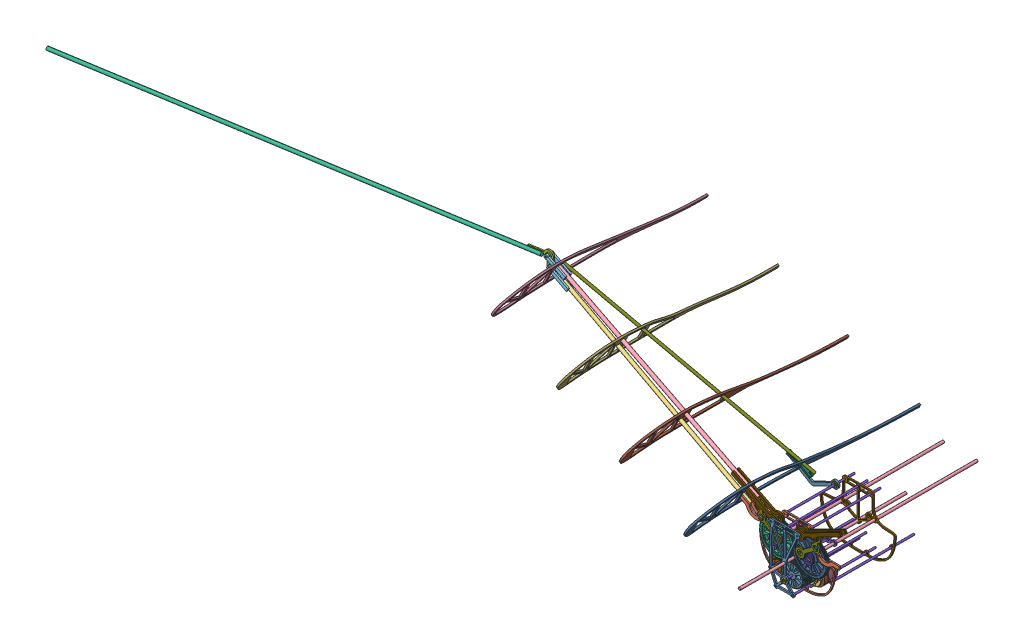
SolidWorks assembly Bird, configuration Default. Lengths in mm.
Overall size (1195.65 218.89 291.06).
74 component instances, 34 part files, 186 mates.
Components (placement in the parent):
- front-plate-sheet-1: front-plate-sheet [Default] at (23.6998 45.889 47.857) size (37.18 69.87 1.59)
- main-gear-sheet-1: main-gear-sheet [Default] at (27.6998 38.7802 32.2695) size (90.47 70.89 1.59)
- motor-mount-sheet-1: motor-mount-sheet [Default] at (23.6998 63.3802 26.2695) size (46 44.87 1.59)
- rod 3mm-1: rod 3mm [Default] at (27.6998 38.7802 103.1929) x (-0.690539 -0.723295 0) z (0 0 1) size (3 3 200)
- rod 3mm-2: rod 3mm [Default] at (7.6998 49.5302 37.857) x (-0.999697 -0.024626 0) z (0 0 1) size (3 3 200)
- rod 3mm-3: rod 3mm [Default] at (47.6998 49.5302 37.857) x (-0.465971 0.8848 0) z (0 0 1) size (3 3 200)
- 3x7mm-1: 3x7mm [Default] at (7.6998 49.5302 34.857) x (0.998777 0.049435 0) z (0 0 1) size (7 7 3)
- 3x7mm-2: 3x7mm [Default] at (47.6998 49.5302 34.857) x (0.999339 0.036342 0) z (0 0 1) size (7 7 3)
- 40mm 80T-1: 40mm 80T [Gear Blank] at (7.6998 49.5302 39.857) x (-0.995675 -0.092905 0) z (0 0 -1) size (41 41 5)
- 2x6x3mm-1: 2x6x3mm [Default] at (10.772 25.7276 32.857) x (-0.923728 -0.383049 0) z (0 0 -1) size (6 6 3)
- rod 2mm-1: rod 2mm [Default] at (17.8846 9.9139 -50.5555) x (-0.006595 0.999978 0) z (0 0 1) size (2 2 100)
- rod 2mm-2: rod 2mm [Default] at (37.5149 9.9139 -50.5555) x (0.478687 0.877986 0) z (0 0 1) size (2 2 100)
- rod 2mm-3: rod 2mm [Default] at (-12.7892 31.2227 -66.143) x (-0.311114 0.950373 0) z (0 0 1) size (2 2 100)
- rod 2mm-4: rod 2mm [Default] at (43.1998 74.5302 -50.5555) x (0.124758 0.992187 0) z (0 0 1) size (2 2 100)
- rod 2mm-5: rod 2mm [Default] at (12.1998 74.5302 -50.5555) x (0.128243 0.991743 0) z (0 0 1) size (2 2 100)
- rod 2mm-6: rod 2mm [Default] at (68.1888 31.2227 -66.143) x (0.415528 -0.90958 0) z (0 0 1) size (2 2 100)
- rod 2mm-7: rod 2mm [Default] at (10.772 25.7276 -50.5555) x (0.356707 -0.934216 0) z (0 0 1) size (2 2 100)
- rod 2mm-8: rod 2mm [Default] at (27.6998 74.5302 -50.5555) x (-0.312804 0.949818 0) z (0 0 1) size (2 2 100)
- 16-60 dual gear (6mm)-1: 16-60 dual gear (6mm) [Default] at (24.6479 25.9831 44.1759) x (0.280286 0.959916 0) z (0 0 1) size (31 31 11)
- 40mm 80T offset-1: 40mm 80T offset [Gear Blank] at (47.6998 49.5302 39.857) x (-0.998555 0.053744 0) z (0 0 -1) size (41 41 5)
- motor-1: motor [Varsayılan] at (41.9632 20.5223 39.6234) x (-0.707107 -0.707107 0) z (0 0 -1) size (28.46 28.46 36)
  - motor-taban-1: motor-taban [Varsayılan] at (-1.063 0.0213 13.3538) size (21 21 15.29)
  - motor-strator-1: motor-strator [Varsayılan] at (-1.063 0.0213 14.1462) x (-0.892183 0.451675 0) z (0 0 1) size (16.41 16.24 8.71)
  - motor-can-1: motor-can [Varsayılan] at (-1.063 0.0213 13.6462) x (-0.47572 0.879597 0) z (0 0 1) size (21 21 36)
- 10-50t dual gear-1: 10-50t dual gear [Default] at (28.1464 26.8366 25.7255) x (-0.859752 -0.510712 0) z (0 0 1) size (25.98 26 11)
- 2x6x3mm-2: 2x6x3mm [Default] at (27.6998 21.289 47.857) x (0.941098 0.338133 0) z (0 0 1) size (6 6 3)
- 2x6x3mm-3: 2x6x3mm [Default] at (27.6998 21.289 24.857) size (6 6 3)
- rod 2mm-9: rod 2mm [Default] at (27.6998 21.289 -49.143) x (0.680803 -0.732466 0) z (0 0 1) size (2 2 100)
- 10T 2mm bore pinion-1: 10T 2mm bore pinion [Gear Blank] at (42.6998 21.289 38.857) x (-0.66586 -0.746077 0) z (0 0 -1) size (6 6 10)
- link-1: link [Default] at (13.8674 53.9021 42.857) x (0.594759 0.803904 0) z (0 0 1) size (18.93 41.68 1.59)
- gear mount-1: gear mount [Default] at (-2.1782 3.169 39.857) x (0.995675 -0.092905 0) z (0 0 1) size (16.05 13.28 1.59)
- gear mount-2: gear mount [Default] at (-19.5287 111.9463 39.857) x (-0.417379 -0.908732 0) z (0 0 1) size (16.05 13.28 1.59)
- link-2: link [Default] at (41.5321 53.9021 44.447) x (-0.594759 0.803904 0) z (0 0 -1) size (18.93 41.68 1.59)
- wing root-1: wing root [Default] at (-6.1886 79.221 45.447) x (0.977458 -0.211132 0) z (0 0 1) size (302 82.72 2)
- wing root-2: wing root [Default] at (-6.1886 79.221 39.447) x (0.977458 -0.211132 0) z (0 0 1) size (302 82.72 2)
- wing root-3: wing root [Default] at (61.5881 79.221 47.037) x (-0.977458 -0.211132 0) z (0 0 -1) size (302 82.72 2)
- wing root-4: wing root [Default] at (61.5881 79.221 41.447) x (-0.977458 -0.211132 0) z (0 0 -1) size (302 82.72 2)
- 2x6x3mm-4: 2x6x3mm [Default] at (13.8674 53.9021 41.447) x (0.95095 0.309345 0) z (0 0 1) size (6 6 3)
- 2x6x3mm-5: 2x6x3mm [Default] at (41.5321 53.9021 41.447) x (0.95095 0.309345 0) z (0 0 1) size (6 6 3)
- 2x6x3mm-6: 2x6x3mm [Default] at (61.5881 79.221 41.447) x (0.95095 0.309345 0) z (0 0 1) size (6 6 3)
- 2x6x3mm-7: 2x6x3mm [Default] at (43.1998 74.5302 44.037) x (0.95095 0.309345 0) z (0 0 1) size (6 6 3)
- 2x6x3mm-8: 2x6x3mm [Default] at (-6.1886 79.221 41.447) x (0.95095 0.309345 0) z (0 0 1) size (6 6 3)
- 2x6x3mm-9: 2x6x3mm [Default] at (43.1998 74.5302 38.447) x (0.96189 0.273438 0) z (0 0 1) size (6 6 3)
- rod 2mm short-1: rod 2mm short [Default] at (61.5881 79.221 39.857) x (-0.312804 0.949818 0) z (0 0 1) size (2 2 8)
- rod 2mm short-2: rod 2mm short [Default] at (-6.1886 79.221 46.827) x (-0.312804 0.949818 0) z (0 0 1) size (2 2 8)
- 2x6x3mm-12: 2x6x3mm [Default] at (12.1998 74.5302 44.447) x (0.96189 0.273438 0) z (0 0 1) size (6 6 3)
- 2x6x3mm-13: 2x6x3mm [Default] at (12.1998 74.5302 38.447) x (0.96189 0.273438 0) z (0 0 1) size (6 6 3)
- actuator link bent-1: actuator link bent [Default] at (-4.7792 67.6976 45.447) x (0.989561 -0.144112 0) z (-0.144112 -0.989561 0) size (26.71 1.59 13.97)
- 2x6x3mm-14: 2x6x3mm [Default] at (-4.7792 67.6976 41.447) x (0.95095 0.309345 0) z (0 0 1) size (6 6 3)
- rod 2mm short-3: rod 2mm short [Default] at (-4.7792 67.6976 46.417) x (-0.312804 0.949818 0) z (0 0 1) size (2 2 8)
- actuator-1: actuator [Default] at (-6.0639 68.2512 43.4737) x (0.883027 -0.469323 0) z (0.107028 0.201373 0.97365) size (263.89 4 4)
- main spar-1: main spar [Default] at (2.7906 88.4475 48.7353) x (0.89269 -0.450672 0) z (0.244604 0.484512 -0.839891) size (270.64 4 4)
- 2x6x3mm-15: 2x6x3mm [Default] at (-257.2865 201.9035 42.447) x (-0.144801 -0.989461 0) z (0 0 1) size (6 6 3)
- 2x6x3mm-16: 2x6x3mm [Default] at (-260.6428 212.2739 42.447) x (-0.144801 -0.989461 0) z (0 0 1) size (6 6 3)
- rod 2mm short-4: rod 2mm short [Default] at (-257.2865 201.9035 46.827) x (0.989981 -0.141199 0) z (0 0 1) size (2 2 8)
- rod 2mm short-5: rod 2mm short [Default] at (-260.6428 212.2739 46.827) x (0.989981 -0.141199 0) z (0 0 1) size (2 2 8)
- actuator link-3: actuator link [Default] at (-260.6428 212.2739 39.447) x (-0.99237 0.123295 0) z (0.123295 0.99237 0) size (286.45 2 106.06)
- actuator link-4: actuator link [Default] at (-260.6428 212.2739 45.447) x (-0.99237 0.123295 0) z (0.123295 0.99237 0) size (286.45 2 106.06)
- actuator link-6: actuator link [Default] at (-257.2865 201.9035 39.447) x (-0.989561 0.144112 0) z (0.144112 0.989561 0) size (286.45 2 106.06)
- actuator link-7: actuator link [Default] at (-257.2865 201.9035 45.447) x (-0.989561 0.144112 0) z (0.144112 0.989561 0) size (286.45 2 106.06)
- actuator link bent-2: actuator link bent [Default] at (-4.7792 67.6976 39.857) x (0.989561 -0.144112 0) z (-0.144112 -0.989561 0) size (26.71 1.59 13.97)
- hand spar-1: hand spar [Default] at (-266.9264 211.3982 46.037) x (-0.011168 0.080129 -0.996722) z (-0.990427 -0.138036 0) size (4 4 600)
- joint-2: joint [Default] at (-257.2865 201.9035 42.447) x (0.951411 0.307925 0) z (0 0 1) size (30.96 22.8 1.59)
- rear support link-1: rear support link [Default] at (27.6998 38.7802 8.5681) size (46 17.13 1.59)
- rear large sheet-1: rear large sheet [Default] at (27.6998 38.7802 -40.5337) size (90.47 70.89 1.59)
- actuator link bent-10: actuator link bent [Default] at (60.8781 58.4075 41.447) x (-0.939246 0.343245 0) z (-0.343245 -0.939246 0) size (26.71 1.59 13.97)
- rib1-1: rib1 [Default] at (359.4585 846.6983 420.0886) x (0.89269 -0.450672 0) z (0.450672 0.89269 0) size (2 290.06 47.22)
- rib2-1: rib2 [Default] at (245.7355 811.2571 420.0886) x (0.89269 -0.450672 0) z (0.450672 0.89269 0) size (2 281.57 47.39)
- rib3-1: rib3 [Default] at (131.6194 775.0372 420.0886) x (0.89269 -0.450672 0) z (0.450672 0.89269 0) size (2 271.54 46.92)
- rib4-1: rib4 [Default] at (17.9807 739.7631 420.0886) x (0.89269 -0.450672 0) z (0.450672 0.89269 0) size (2 263.69 44.4)
- secondary root-1: secondary root [Default] at (12.1998 74.5302 -26.8269) x (-0.999998 -0.002177 0) z (0.002177 -0.999998 0) size (60.65 2 20.92)
- 2x6x3mm-20: 2x6x3mm [Default] at (12.1998 74.5302 -28.8269) x (0.96189 0.273438 0) z (0 0 1) size (6 6 3)
- secondary spar mount-1: secondary spar mount [Default] at (-19.1114 66.1726 -34.0472) x (-0.859481 0.511168 0) z (0 0 -1) size (29.79 2 10.44)
- secondary spar-1: secondary spar [Default] at (-16.9984 68.9882 -32.5953) x (-0.540081 -0.825896 -0.161889) z (-0.831916 0.494774 0.251225) size (3 3 279)
Mates (geometry in assembly coordinates):
- Concentric1: concentric aligned: cylinder of main-gear-sheet-1 through (17.8846 9.9139 33.857) axis (0 0 -1) radius 1; cylinder of motor-mount-sheet-1 through (17.8846 9.9139 27.857) axis (0 0 -1) radius 1
- Concentric2: concentric aligned: cylinder of main-gear-sheet-1 through (17.8846 9.9139 33.857) axis (0 0 -1) radius 1; cylinder of front-plate-sheet-1 through (17.8846 9.9139 49.4445) axis (0 0 -1) radius 1
- Concentric3: concentric aligned: cylinder of main-gear-sheet-1 through (27.6998 38.7802 33.857) axis (0 0 -1) radius 1.5; cylinder of motor-mount-sheet-1 through (27.6998 38.7802 27.857) axis (0 0 -1) radius 1.5
- Concentric4: concentric aligned: cylinder of main-gear-sheet-1 through (27.6998 38.7802 33.857) axis (0 0 -1) radius 1.5; cylinder of front-plate-sheet-1 through (27.6998 38.7802 49.4445) axis (0 0 -1) radius 1.5
- Concentric5: concentric anti-aligned: cylinder of motor-mount-sheet-1 through (27.6998 38.7802 27.857) axis (0 0 -1) radius 1.5; cylinder of rod 3mm-1 through (27.6998 38.7802 -96.8071) axis (0 0 1) radius 1.5
- Concentric7: concentric anti-aligned: cylinder of main-gear-sheet-1 through (47.6998 49.5302 33.857) axis (0 0 -1) radius 1.5; cylinder of rod 3mm-3 through (47.6998 49.5302 -162.143) axis (0 0 1) radius 1.5
- Concentric8: concentric anti-aligned: cylinder of motor-mount-sheet-1 through (7.6998 49.5302 27.857) axis (0 0 -1) radius 1.5; cylinder of rod 3mm-2 through (7.6998 49.5302 -162.143) axis (0 0 1) radius 1.5
- Concentric11: concentric anti-aligned: cylinder of rod 3mm-3 through (47.6998 49.5302 -162.143) axis (0 0 1) radius 1.5; cylinder of 3x7mm-2 through (47.6998 49.5302 37.857) axis (0 0 -1) radius 1.5
- Concentric12: concentric anti-aligned: cylinder of rod 3mm-2 through (7.6998 49.5302 -162.143) axis (0 0 1) radius 1.5; cylinder of 3x7mm-1 through (7.6998 49.5302 37.857) axis (0 0 -1) radius 1.5
- Concentric13: concentric anti-aligned: cylinder of 3x7mm-1 through (7.6998 49.5302 37.857) axis (0 0 -1) radius 3.5; cylinder of 40mm 80T-1 through (7.6998 49.5302 34.857) axis (0 0 1) radius 3.5
- Concentric14: concentric anti-aligned: cylinder of 3x7mm-2 through (47.6998 49.5302 44.7429) axis (0 0 -1) radius 3.5; cylinder of ? through (47.6998 49.5302 41.7429) axis (0 0 1) radius 3.5
- Distance1: distance = 1 mm anti-aligned: plane of 3x7mm-2 through (47.6998 49.5302 34.857) normal (0 0 -1); plane of main-gear-sheet-1 through (27.6998 38.7802 33.857) normal (0 0 1)
- Coincident7: coincident aligned: plane of 3x7mm-2 through (47.6998 49.5302 41.7429) normal (0 0 -1); plane of ? through (47.9996 69.7817 41.7429) normal (0 0 -1)
- Coincident8: coincident aligned: plane of 3x7mm-1 through (7.6998 49.5302 34.857) normal (0 0 -1); plane of 40mm 80T-1 through (6.1168 69.722 34.857) normal (0 0 -1)
- Coincident10: coincident aligned: plane of 3x7mm-1 through (7.6998 49.5302 34.857) normal (0 0 -1); plane of 3x7mm-2 through (47.6998 49.5302 34.857) normal (0 0 -1)
- Concentric16: concentric aligned: cylinder of front-plate-sheet-1 through (10.772 25.7276 49.4445) axis (0 0 -1) radius 0.75; cylinder of ? through (10.772 25.7276 80.4555) axis (0 0 -1) radius 0.75
- Concentric18: concentric anti-aligned: cylinder of ? through (10.772 25.7276 40.9691) axis (0 0 -1) radius 3; cylinder of 2x6x3mm-1 through (10.772 25.7276 36.9691) axis (0 0 1) radius 3
- Concentric19: concentric aligned: cylinder of front-plate-sheet-1 through (10.772 25.7276 49.4445) axis (0 0 -1) radius 1; cylinder of rod 2mm-7 through (10.772 25.7276 49.4445) axis (0 0 -1) radius 1
- Concentric20: concentric anti-aligned: cylinder of 2x6x3mm-1 through (10.772 25.7276 29.857) axis (0 0 1) radius 1; cylinder of rod 2mm-7 through (10.772 25.7276 49.4445) axis (0 0 -1) radius 1
- Distance3: distance = 1 mm aligned: plane of 2x6x3mm-1 through (10.772 25.7276 36.9691) normal (0 0 -1); plane of ? through (10.6831 10.4779 35.9691) normal (0 0 -1)
- Distance4: distance = 1 mm anti-aligned: plane of ? through (10.6831 10.4779 40.9691) normal (0 0 1); plane of 40mm 80T-1 through (20.7187 65.0454 41.9691) normal (0 0 -1)
- Concentric21: concentric anti-aligned: cylinder of 2x6x3mm-1 through (10.772 25.7276 29.857) axis (0 0 1) radius 3; cylinder of 16-60 dual gear (6mm)-1 through (10.772 25.7276 33.857) axis (0 0 -1) radius 3
- Distance5: distance = 1 mm anti-aligned: plane of 16-60 dual gear (6mm)-1 through (6.5942 26.6472 33.857) normal (0 0 -1); plane of 2x6x3mm-1 through (10.772 25.7276 32.857) normal (0 0 1)
- Coincident15: coincident aligned: plane of 40mm 80T-1 through (6.1168 69.722 39.857) normal (0 0 1); plane of 16-60 dual gear (6mm)-1 through (6.5942 26.6472 39.857) normal (0 0 1)
- GearMate3: gear = 16 : 80 mm: circle of 40mm 80T-1; circle of 16-60 dual gear (6mm)-1
- Concentric23: concentric aligned: cylinder of main-gear-sheet-1 through (17.8846 9.9139 33.857) axis (0 0 -1) radius 1; cylinder of rod 2mm-1 through (17.8846 9.9139 49.4445) axis (0 0 -1) radius 1
- Concentric24: concentric aligned: cylinder of main-gear-sheet-1 through (37.5149 9.9139 33.857) axis (0 0 -1) radius 1; cylinder of rod 2mm-2 through (37.5149 9.9139 49.4445) axis (0 0 -1) radius 1
- Concentric25: concentric aligned: cylinder of main-gear-sheet-1 through (-12.7892 31.2227 33.857) axis (0 0 -1) radius 1; cylinder of rod 2mm-3 through (-12.7892 31.2227 33.857) axis (0 0 -1) radius 1
- Concentric26: concentric aligned: cylinder of main-gear-sheet-1 through (68.1888 31.2227 33.857) axis (0 0 -1) radius 1; cylinder of rod 2mm-6 through (68.1888 31.2227 33.857) axis (0 0 -1) radius 1
- Concentric27: concentric aligned: cylinder of main-gear-sheet-1 through (12.1998 74.5302 33.857) axis (0 0 -1) radius 1; cylinder of rod 2mm-5 through (12.1998 74.5302 49.4445) axis (0 0 -1) radius 1
- Concentric28: concentric aligned: cylinder of main-gear-sheet-1 through (43.1998 74.5302 33.857) axis (0 0 -1) radius 1; cylinder of rod 2mm-4 through (43.1998 74.5302 49.4445) axis (0 0 -1) radius 1
- Concentric29: concentric aligned: cylinder of main-gear-sheet-1 through (27.6998 74.5302 33.857) axis (0 0 -1) radius 1; cylinder of rod 2mm-8 through (27.6998 74.5302 49.4445) axis (0 0 -1) radius 1
- Concentric36: concentric anti-aligned: cylinder of 3x7mm-2 through (47.6998 49.5302 37.857) axis (0 0 -1) radius 3.5; cylinder of 40mm 80T offset-1 through (47.6998 49.5302 34.857) axis (0 0 1) radius 3.5
- Coincident19: coincident aligned: plane of 40mm 80T-1 through (6.1168 69.722 39.857) normal (0 0 1); plane of 40mm 80T offset-1 through (49.0876 69.7363 39.857) normal (0 0 1)
- Concentric37: concentric anti-aligned: cylinder of motor-mount-sheet-1 through (42.6998 29.289 27.857) axis (0 0 -1) radius 1.05; cylinder of motor-1/motor-taban-1 through (42.6998 29.289 21.7695) axis (0 0 1) radius 1
- Concentric38: concentric anti-aligned: cylinder of motor-mount-sheet-1 through (42.6998 13.289 27.857) axis (0 0 -1) radius 1.05; cylinder of motor-1/motor-taban-1 through (42.6998 13.289 21.7695) axis (0 0 1) radius 1
- Coincident20: coincident anti-aligned: plane of motor-mount-sheet-1 through (7.6998 49.5302 26.2695) normal (0 0 -1); plane of motor-1/motor-taban-1 through (42.6998 21.289 26.2695) normal (0 0 1)
- Concentric39: concentric aligned: cylinder of motor-mount-sheet-1 through (42.6998 13.289 34.9446) axis (0 0 -1) radius 1.05; cylinder of ? through (42.6998 13.289 44.6736) axis (0 0 -1) radius 1.187
- Concentric40: concentric aligned: cylinder of front-plate-sheet-1 through (27.6998 21.289 49.4445) axis (0 0 -1) radius 3; cylinder of 2x6x3mm-2 through (27.6998 21.289 50.857) axis (0 0 -1) radius 3
- Concentric43: concentric aligned: cylinder of front-plate-sheet-1 through (27.6998 21.289 49.4445) axis (0 0 -1) radius 3; cylinder of motor-mount-sheet-1 through (27.6998 21.289 27.857) axis (0 0 -1) radius 3
- Concentric44: concentric aligned: cylinder of front-plate-sheet-1 through (27.6998 21.289 49.4445) axis (0 0 -1) radius 3; cylinder of 2x6x3mm-2 through (27.6998 21.289 50.857) axis (0 0 -1) radius 3
- Coincident21: coincident aligned: plane of front-plate-sheet-1 through (12.1998 74.5302 47.857) normal (0 0 -1); plane of 2x6x3mm-2 through (27.6998 21.289 47.857) normal (0 0 -1)
- Concentric45: concentric aligned: cylinder of motor-mount-sheet-1 through (27.6998 21.289 27.857) axis (0 0 -1) radius 3; cylinder of 2x6x3mm-3 through (27.6998 21.289 27.857) axis (0 0 -1) radius 3
- Coincident22: coincident aligned: plane of motor-mount-sheet-1 through (7.6998 49.5302 27.857) normal (0 0 1); plane of 2x6x3mm-3 through (27.6998 21.289 27.857) normal (0 0 1)
- Concentric46: concentric aligned: cylinder of 2x6x3mm-2 through (27.6998 21.289 50.857) axis (0 0 -1) radius 1; cylinder of rod 2mm-9 through (27.6998 21.289 50.857) axis (0 0 -1) radius 1
- Concentric47: concentric aligned: cylinder of 10-50t dual gear-1 through (27.6998 21.289 34.857) axis (0 0 -1) radius 1; cylinder of rod 2mm-9 through (27.6998 21.289 50.857) axis (0 0 -1) radius 1
- Coincident23: coincident aligned: plane of 16-60 dual gear (6mm)-1 through (6.5942 26.6472 39.857) normal (0 0 1); plane of 10-50t dual gear-1 through (23.9879 33.4851 39.857) normal (0 0 1)
- GearMate5: gear = 60 : 10 mm: cylinder of 10-50t dual gear-1 through (27.6998 21.289 39.857) axis (0 0 -1) radius 4; cylinder of 16-60 dual gear (6mm)-1 through (10.772 25.7276 28.857) axis (0 0 1) radius 6
- Distance6: distance = 8 mm anti-aligned: plane of 10-50t dual gear-1 through (23.9879 33.4851 39.857) normal (0 0 1); plane of front-plate-sheet-1 through (12.1998 74.5302 47.857) normal (0 0 -1)
- Distance7: distance = 1 mm anti-aligned: plane of motor-mount-sheet-1 through (7.6998 49.5302 27.857) normal (0 0 1); plane of 16-60 dual gear (6mm)-1 through (-3.9483 29.712 28.857) normal (0 0 -1)
- Concentric49: concentric anti-aligned: cylinder of motor-1/motor-can-1 through (42.6998 21.289 40.9772) axis (0 0 -1) radius 0.75; cylinder of 10T 2mm bore pinion-1 through (42.6998 21.289 29.857) axis (0 0 1) radius 1
- Coincident26: coincident aligned: plane of 10-50t dual gear-1 through (23.9879 33.4851 39.857) normal (0 0 1); plane of 10T 2mm bore pinion-1 through (40.8007 23.3514 39.857) normal (0 0 1)
- GearMate6: gear = 10 : 50 mm: cylinder of 10-50t dual gear-1 through (27.6998 21.289 39.857) axis (0 0 -1) radius 4; cylinder of 10T 2mm bore pinion-1 through (42.6998 21.289 33.857) axis (0 0 1) radius 3
- Coincident27: coincident aligned: plane of main-gear-sheet-1 through (27.6998 38.7802 33.857) normal (0 0 1); plane of rod 2mm-6 through (68.1888 31.2227 33.857) normal (0 0 1)
- Coincident28: coincident aligned: plane of main-gear-sheet-1 through (27.6998 38.7802 33.857) normal (0 0 1); plane of rod 2mm-3 through (-12.7892 31.2227 33.857) normal (0 0 1)
- Coincident29: coincident aligned: plane of front-plate-sheet-1 through (12.1998 74.5302 49.4445) normal (0 0 1); plane of rod 2mm-5 through (12.1998 74.5302 49.4445) normal (0 0 1)
- Coincident30: coincident aligned: plane of front-plate-sheet-1 through (12.1998 74.5302 49.4445) normal (0 0 1); circle of rod 2mm-4
- Coincident31: coincident aligned: plane of rod 3mm-3 through (47.6998 49.5302 37.857) normal (0 0 1); plane of 3x7mm-2 through (47.6998 49.5302 37.857) normal (0 0 1)
- Coincident32: coincident aligned: plane of rod 3mm-2 through (7.6998 49.5302 37.857) normal (0 0 1); plane of 3x7mm-1 through (7.6998 49.5302 37.857) normal (0 0 1)
- Coincident33: coincident aligned: plane of front-plate-sheet-1 through (12.1998 74.5302 49.4445) normal (0 0 1); plane of rod 2mm-2 through (37.5149 9.9139 49.4445) normal (0 0 1)
- Coincident34: coincident aligned: plane of 2x6x3mm-2 through (27.6998 21.289 50.857) normal (0 0 1); plane of rod 2mm-9 through (27.6998 21.289 50.857) normal (0 0 1)
- Coincident35: coincident aligned: plane of front-plate-sheet-1 through (12.1998 74.5302 49.4445) normal (0 0 1); plane of rod 2mm-7 through (10.772 25.7276 49.4445) normal (0 0 1)
- Coincident36: coincident aligned: plane of front-plate-sheet-1 through (12.1998 74.5302 49.4445) normal (0 0 1); plane of rod 2mm-1 through (17.8846 9.9139 49.4445) normal (0 0 1)
- Coincident37: coincident aligned: plane of front-plate-sheet-1 through (12.1998 74.5302 49.4445) normal (0 0 1); plane of rod 2mm-8 through (27.6998 74.5302 49.4445) normal (0 0 1)
- Concentric50: concentric anti-aligned: cylinder of 40mm 80T-1 through (7.6998 49.5302 34.857) axis (0 0 1) radius 3.5; cylinder of gear mount-2 through (7.6998 49.5302 41.447) axis (0 0 -1) radius 3.5
- Coincident38: coincident anti-aligned: plane of 40mm 80T-1 through (6.1168 69.722 39.857) normal (0 0 1); plane of gear mount-2 through (-19.5287 111.9463 39.857) normal (0 0 -1)
- Concentric51: concentric anti-aligned: cylinder of 40mm 80T-1 through (12.2434 47.4433 37.857) axis (0 0 1) radius 1.5; cylinder of gear mount-2 through (12.2434 47.4433 41.447) axis (0 0 -1) radius 0.575
- Concentric52: concentric anti-aligned: cylinder of 40mm 80T offset-1 through (47.6998 49.5302 34.857) axis (0 0 1) radius 3.5; cylinder of gear mount-1 through (47.6998 49.5302 41.447) axis (0 0 -1) radius 3.5
- Coincident39: coincident anti-aligned: plane of 40mm 80T offset-1 through (49.0876 69.7363 39.857) normal (0 0 1); plane of gear mount-1 through (-2.1782 3.169 39.857) normal (0 0 -1)
- Concentric53: concentric anti-aligned: cylinder of 40mm 80T offset-1 through (43.1561 47.4433 37.857) axis (0 0 1) radius 1.5; cylinder of gear mount-1 through (43.1561 47.4433 41.447) axis (0 0 -1) radius 0.575
- Concentric54: concentric aligned: cylinder of link-1 through (13.8674 53.9021 44.447) axis (0 0 -1) radius 3; cylinder of gear mount-2 through (13.8674 53.9021 41.447) axis (0 0 -1) radius 1
- Concentric55: concentric anti-aligned: cylinder of gear mount-1 through (41.5321 53.9021 41.447) axis (0 0 -1) radius 1; cylinder of link-2 through (41.5321 53.9021 42.857) axis (0 0 1) radius 3
- Concentric60: concentric anti-aligned: cylinder of rod 2mm-4 through (43.1998 74.5302 49.4445) axis (0 0 -1) radius 1; cylinder of wing root-3 through (43.1998 74.5302 45.037) axis (0 0 1) radius 3
- Concentric62: concentric anti-aligned: cylinder of rod 2mm-4 through (43.1998 74.5302 49.4445) axis (0 0 -1) radius 1; cylinder of wing root-4 through (43.1998 74.5302 39.447) axis (0 0 1) radius 3
- Concentric63: concentric aligned: cylinder of wing root-3 through (61.5881 79.221 45.037) axis (0 0 1) radius 1; cylinder of wing root-4 through (61.5881 79.221 39.447) axis (0 0 1) radius 1
- Concentric64: concentric aligned: cylinder of link-1 through (13.8674 53.9021 44.447) axis (0 0 -1) radius 3; cylinder of 2x6x3mm-4 through (13.8674 53.9021 44.447) axis (0 0 -1) radius 3
- Coincident46: coincident anti-aligned: plane of gear mount-2 through (-19.5287 111.9463 41.447) normal (0 0 1); plane of 2x6x3mm-4 through (13.8674 53.9021 41.447) normal (0 0 -1)
- Concentric65: concentric anti-aligned: cylinder of link-2 through (41.5321 53.9021 42.857) axis (0 0 1) radius 3; cylinder of 2x6x3mm-5 through (41.5321 53.9021 44.447) axis (0 0 -1) radius 3
- Coincident47: coincident anti-aligned: plane of gear mount-1 through (-2.1782 3.169 41.447) normal (0 0 1); plane of 2x6x3mm-5 through (41.5321 53.9021 41.447) normal (0 0 -1)
- Concentric68: concentric anti-aligned: cylinder of wing root-4 through (43.1998 74.5302 39.447) axis (0 0 1) radius 3; cylinder of 2x6x3mm-9 through (43.1998 74.5302 41.447) axis (0 0 -1) radius 3
- Concentric69: concentric anti-aligned: cylinder of wing root-3 through (43.1998 74.5302 45.037) axis (0 0 1) radius 3; cylinder of 2x6x3mm-7 through (43.1998 74.5302 47.037) axis (0 0 -1) radius 3
- Concentric70: concentric anti-aligned: cylinder of wing root-3 through (61.5881 79.221 45.037) axis (0 0 1) radius 1; cylinder of rod 2mm short-1 through (61.5881 79.221 43.3054) axis (0 0 -1) radius 1
- Concentric72: concentric aligned: cylinder of rod 2mm-5 through (12.1998 74.5302 49.4445) axis (0 0 -1) radius 1; cylinder of 2x6x3mm-13 through (12.1998 74.5302 41.447) axis (0 0 -1) radius 3
- Concentric73: concentric aligned: cylinder of 2x6x3mm-12 through (12.1998 74.5302 47.447) axis (0 0 -1) radius 3; cylinder of 2x6x3mm-13 through (12.1998 74.5302 41.447) axis (0 0 -1) radius 3
- Coincident66: coincident aligned: plane of link-1 through (13.8674 53.9021 44.447) normal (0 0 1); plane of 2x6x3mm-8 through (-6.1886 79.221 44.447) normal (0 0 1)
- Coincident71: coincident aligned: plane of link-2 through (41.5321 53.9021 44.447) normal (0 0 1); plane of 2x6x3mm-6 through (61.5881 79.221 44.447) normal (0 0 1)
- Coincident72: coincident aligned: plane of link-2 through (41.5321 53.9021 44.447) normal (0 0 1); plane of 2x6x3mm-5 through (41.5321 53.9021 44.447) normal (0 0 1)
- Coincident74: coincident aligned: plane of link-1 through (13.8674 53.9021 44.447) normal (0 0 1); plane of 2x6x3mm-4 through (13.8674 53.9021 44.447) normal (0 0 1)
- Concentric75: concentric anti-aligned: circle of actuator link bent-1; cylinder of ? through (-5.5274 56.9935 41.447) axis (0 0 -1) radius 1
- Coincident77: coincident aligned: plane of wing root-1 through (-14.2284 73.732 41.447) normal (0 0 1); plane of ? through (-5.5274 56.9935 41.447) normal (0 0 1)
- Concentric76: concentric aligned: cylinder of 2x6x3mm-8 through (-6.1886 79.221 44.447) axis (0 0 -1) radius 1; cylinder of rod 2mm short-2 through (-6.1886 79.221 50.2754) axis (0 0 -1) radius 1
- Concentric78: concentric aligned: cylinder of 2x6x3mm-6 through (61.5881 79.221 44.447) axis (0 0 -1) radius 1; cylinder of rod 2mm short-1 through (61.5881 79.221 43.3054) axis (0 0 -1) radius 1
- Concentric80: concentric aligned: cylinder of link-1 through (-4.7792 67.6976 44.447) axis (0 0 -1) radius 3; cylinder of 2x6x3mm-14 through (-4.7792 67.6976 44.447) axis (0 0 -1) radius 3
- Coincident78: coincident aligned: plane of link-1 through (13.8674 53.9021 44.447) normal (0 0 1); plane of 2x6x3mm-14 through (-4.7792 67.6976 44.447) normal (0 0 1)
- Concentric83: concentric aligned: cylinder of actuator link bent-1 through (-4.7792 67.6976 47.037) axis (0 0 -1) radius 1; cylinder of rod 2mm short-3 through (-4.7792 67.6976 49.8654) axis (0 0 -1) radius 1
- Coincident80: coincident aligned: plane of actuator link bent-1 through (-4.7792 67.6976 47.037) normal (0 0 1); plane of rod 2mm short-3 through (-10.0286 69.3391 47.037) normal (0 0 1)
- Coincident81: coincident aligned: plane of actuator link bent-1; plane of ? through (-5.2612 58.9757 41.447) normal (0.133091 0.991104 0)
- Concentric84: concentric aligned: cylinder of wing root-1 through (-6.1886 79.221 47.447) axis (0 0 -1) radius 1; cylinder of rod 2mm short-2 through (-6.1886 79.221 50.2754) axis (0 0 -1) radius 1
- Tangent1: tangent anti-aligned: plane of actuator link bent-1 through (-4.7792 67.6976 45.447) normal (0 0 -1); cylinder of actuator-1 through (-251.5468 198.8529 43.447) axis (0.883027 -0.469323 0) radius 2
- Tangent2: tangent aligned: plane of actuator link bent-1 through (-3.8406 69.4636 47.037) normal (0.469323 0.883027 0); cylinder of actuator-1 through (-251.5468 198.8529 43.447) axis (0.883027 -0.469323 0) radius 2
- Coincident84: coincident aligned: plane of ? through (-185.4714 321.1453 42.447) normal (0 0 -1); plane of 2x6x3mm-16 through (-180.1902 331.9207 42.447) normal (0 0 -1)
- Coincident85: coincident aligned: plane of ? through (-185.4714 321.1453 42.447) normal (0 0 -1); plane of 2x6x3mm-15 through (-185.4714 321.1453 42.447) normal (0 0 -1)
- Concentric86: concentric aligned: cylinder of 2x6x3mm-15 through (-257.2865 201.9035 45.447) axis (0 0 -1) radius 1; cylinder of rod 2mm short-4 through (-257.2865 201.9035 50.2754) axis (0 0 -1) radius 1
- Concentric87: concentric aligned: cylinder of 2x6x3mm-16 through (-260.6428 212.2739 45.447) axis (0 0 -1) radius 1; cylinder of rod 2mm short-5 through (-260.6428 212.2739 50.2754) axis (0 0 -1) radius 1
- Concentric88: concentric aligned: cylinder of rod 2mm short-5 through (-260.6428 212.2739 50.2754) axis (0 0 -1) radius 1; cylinder of actuator link-3 through (-260.6428 212.2739 41.447) axis (0 0 -1) radius 1
- Concentric89: concentric aligned: cylinder of rod 2mm short-5 through (-260.6428 212.2739 50.2754) axis (0 0 -1) radius 1; cylinder of actuator link-4 through (-260.6428 212.2739 47.447) axis (0 0 -1) radius 1
- Concentric90: concentric aligned: cylinder of rod 2mm short-4 through (-257.2865 201.9035 50.2754) axis (0 0 -1) radius 1; cylinder of actuator link-7 through (-257.2865 201.9035 47.447) axis (0 0 -1) radius 1
- Concentric91: concentric aligned: cylinder of rod 2mm short-4 through (-257.2865 201.9035 50.2754) axis (0 0 -1) radius 1; cylinder of actuator link-6 through (-257.2865 201.9035 41.447) axis (0 0 -1) radius 1
- Coincident86: coincident aligned: plane of rod 2mm short-5 through (-256.8423 216.2495 47.447) normal (0 0 1); plane of actuator link-4 through (-260.6428 212.2739 47.447) normal (0 0 1)
- Coincident87: coincident aligned: plane of rod 2mm short-4 through (-253.4859 205.8792 47.447) normal (0 0 1); plane of actuator link-7 through (-257.2865 201.9035 47.447) normal (0 0 1)
- Coincident89: coincident anti-aligned: plane of 2x6x3mm-16 through (-260.6428 212.2739 45.447) normal (0 0 1); plane of actuator link-4 through (-260.6428 212.2739 45.447) normal (0 0 -1)
- Coincident90: coincident aligned: plane of actuator link-3 through (-261.5442 210.4885 41.447) normal (-0.450672 -0.89269 0); plane of actuator link-4 through (-261.5442 210.4885 47.447) normal (-0.450672 -0.89269 0)
- Coincident92: coincident anti-aligned: plane of 2x6x3mm-15 through (-257.2865 201.9035 45.447) normal (0 0 1); plane of actuator link-7 through (-257.2865 201.9035 45.447) normal (0 0 -1)
- Coincident93: coincident aligned: plane of actuator link-6 through (-258.2251 200.1375 41.447) normal (-0.469323 -0.883027 0); plane of actuator link-7 through (-258.2251 200.1375 47.447) normal (-0.469323 -0.883027 0)
- Coincident95: coincident aligned: plane of rod 2mm short-5 through (-260.6428 212.2739 39.447) normal (0 0 -1); plane of actuator link-3 through (-260.6428 212.2739 39.447) normal (0 0 -1)
- Coincident96: coincident aligned: plane of rod 2mm short-4 through (-257.2865 201.9035 39.447) normal (0 0 -1); plane of actuator link-6 through (-257.2865 201.9035 39.447) normal (0 0 -1)
- Tangent8: tangent anti-aligned: cylinder of main spar-1 through (-250.8233 207.3165 43.447) axis (0.89269 -0.450672 0) radius 2; plane of actuator link-3 through (-260.6428 212.2739 41.447) normal (0 0 1)
- Tangent10: tangent aligned: cylinder of main spar-1 through (-250.8233 207.3165 43.447) axis (0.89269 -0.450672 0) radius 2; plane of actuator link-3 through (-259.7415 214.0593 41.447) normal (0.450672 0.89269 0)
- Coincident99: coincident aligned: plane of actuator link bent-1 through (-3.8406 69.4636 47.037) normal (0.469323 0.883027 0); plane of actuator link-7 through (-256.3478 203.6696 47.447) normal (0.469323 0.883027 0)
- Concentric92: concentric aligned: cylinder of rod 2mm short-3 through (-4.7792 67.6976 49.8654) axis (0 0 -1) radius 1; cylinder of actuator link bent-2 through (-4.7792 67.6976 41.447) axis (0 0 -1) radius 1
- Coincident101: coincident aligned: plane of actuator link bent-1 through (-3.8406 69.4636 47.037) normal (0.469323 0.883027 0); plane of actuator link bent-2 through (-3.8406 69.4636 41.447) normal (0.469323 0.883027 0)
- Tangent15: tangent anti-aligned: plane of ? through (-185.4714 321.1453 44.037) normal (0 0 1); cylinder of hand spar-1 through (-724.1365 598.52 46.037) axis (0.897947 -0.440103 0) radius 2
- Concentric93: concentric aligned: cylinder of ? through (-180.1902 331.9207 44.037) axis (0 0 -1) radius 3; cylinder of 2x6x3mm-16 through (-180.1902 331.9207 45.447) axis (0 0 -1) radius 3
- Concentric95: concentric aligned: cylinder of ? through (-185.4714 321.1453 44.037) axis (0 0 -1) radius 3; cylinder of 2x6x3mm-15 through (-185.4714 321.1453 45.447) axis (0 0 -1) radius 3
- Tangent17: tangent anti-aligned: plane of ? through (-185.4714 321.1453 44.037) normal (0 0 1); cylinder of hand spar-1 through (-724.1365 598.52 46.037) axis (0.897947 -0.440103 0) radius 2
- Tangent18: tangent aligned: plane of ? through (-179.31 333.7166 44.037) normal (0.440103 0.897947 0); cylinder of hand spar-1 through (-724.1365 598.52 46.037) axis (0.897947 -0.440103 0) radius 2
- Coincident104: coincident: line of ? through (-184.4878 336.2543 44.037) axis (0 0 -1); plane of hand spar-1
- Distance14: distance = 5 mm anti-aligned: plane of main spar-1; cylinder of ? through (-180.1902 331.9207 44.037) axis (0 0 -1) radius 5.5
- Distance15: distance = 5 mm anti-aligned: cylinder of ? through (-185.4714 321.1453 44.037) axis (0 0 -1) radius 5.5; plane of actuator-1
- Concentric101: concentric aligned: cylinder of actuator link bent-1 through (-4.7792 67.6976 47.037) axis (0 0 -1) radius 2.5; cylinder of 2x6x3mm-14 through (-4.7792 67.6976 44.447) axis (0 0 -1) radius 1
- Coincident106: coincident: plane of actuator-1 through (-18.5267 75.0042 43.447) normal (0.883027 -0.469323 0); line of actuator link bent-2 through (-17.588 76.7703 41.447) axis (0 0 -1)
- Concentric102: concentric anti-aligned: cylinder of link-2 through (61.5881 79.221 42.857) axis (0 0 1) radius 3; cylinder of 2x6x3mm-6 through (61.5881 79.221 44.447) axis (0 0 -1) radius 3
- Coincident112: coincident aligned: plane of wing root-1 through (-11.4379 80.8625 47.447) normal (0 0 1); plane of 2x6x3mm-12 through (12.1998 74.5302 47.447) normal (0 0 1)
- Concentric106: concentric aligned: cylinder of wing root-1 through (12.1998 74.5302 47.447) axis (0 0 -1) radius 3; cylinder of 2x6x3mm-12 through (12.1998 74.5302 47.447) axis (0 0 -1) radius 3
- Tangent26: tangent aligned: plane of wing root-1 through (6.9649 79.4134 47.447) normal (0.450672 0.89269 0); cylinder of main spar-1 through (-250.8233 207.3165 43.447) axis (0.89269 -0.450672 0) radius 2
- Distance16: distance = 23 mm anti-aligned: cylinder of rod 2mm-5 through (12.1998 74.5302 49.4445) axis (0 0 -1) radius 1; plane of main spar-1 through (-9.2248 85.3463 43.447) normal (0.89269 -0.450672 0)
- Coincident118: coincident anti-aligned: plane of 2x6x3mm-14 through (-4.7792 67.6976 41.447) normal (0 0 -1); plane of actuator link bent-2 through (-4.7792 67.6976 41.447) normal (0 0 1)
- Coincident119: coincident aligned: plane of actuator link-4 through (-260.6428 212.2739 47.447) normal (0 0 1); plane of actuator link-7 through (-257.2865 201.9035 47.447) normal (0 0 1)
- Concentric114: concentric aligned: cylinder of 2x6x3mm-16 through (-260.6428 212.2739 45.447) axis (0 0 -1) radius 3; cylinder of joint-2 through (-260.6428 212.2739 44.037) axis (0 0 -1) radius 3
- Concentric115: concentric aligned: cylinder of 2x6x3mm-15 through (-257.2865 201.9035 45.447) axis (0 0 -1) radius 3; cylinder of joint-2 through (-257.2865 201.9035 44.037) axis (0 0 -1) radius 5.5
- Coincident123: coincident aligned: plane of 2x6x3mm-16 through (-260.6428 212.2739 42.447) normal (0 0 -1); plane of joint-2 through (-257.2865 201.9035 42.447) normal (0 0 -1)
- Distance21: distance = 5.5 mm anti-aligned: plane of main spar-1 through (-250.8233 207.3165 43.447) normal (-0.89269 0.450672 0); cylinder of joint-2 through (-260.6428 212.2739 44.037) axis (0 0 -1) radius 5.5
- Distance22: distance = 1 mm anti-aligned: plane of actuator-1 through (-251.5468 198.8529 43.447) normal (-0.883027 0.469323 0); cylinder of joint-2 through (-257.2865 201.9035 44.037) axis (0 0 -1) radius 5.5
- Tangent36: tangent aligned: cylinder of hand spar-1 through (-861.1827 128.5764 46.037) axis (0.990427 0.138036 0) radius 2; plane of joint-2 through (-259.0443 214.516 44.037) normal (-0.138036 0.990427 0)
- Tangent37: tangent anti-aligned: cylinder of hand spar-1 through (-861.1827 128.5764 46.037) axis (0.990427 0.138036 0) radius 2; plane of joint-2 through (-257.2865 201.9035 44.037) normal (0 0 1)
- Coincident124: coincident: plane of hand spar-1 through (-266.9264 211.3982 46.037) normal (0.990427 0.138036 0); line of joint-2 through (-267.2025 213.379 44.037) axis (0 0 -1)
- Concentric116: concentric anti-aligned: cylinder of rod 3mm-3 through (47.6998 49.5302 -162.143) axis (0 0 1) radius 1.5; cylinder of rear large sheet-1 through (47.6998 49.5302 -38.9462) axis (0 0 -1) radius 1.5
- Concentric117: concentric anti-aligned: cylinder of rod 3mm-2 through (7.6998 49.5302 -162.143) axis (0 0 1) radius 1.5; cylinder of rear large sheet-1 through (7.6998 49.5302 -38.9462) axis (0 0 -1) radius 1.5
- Concentric118: concentric anti-aligned: cylinder of rod 3mm-2 through (7.6998 49.5302 -162.143) axis (0 0 1) radius 1.5; cylinder of rear support link-1 through (7.6998 49.5302 10.1556) axis (0 0 -1) radius 1.5
- Concentric119: concentric anti-aligned: cylinder of rod 3mm-3 through (47.6998 49.5302 -162.143) axis (0 0 1) radius 1.5; cylinder of rear support link-1 through (47.6998 49.5302 10.1556) axis (0 0 -1) radius 1.5
- Coincident168: coincident aligned: plane of actuator link bent-1 through (-8.4975 70.96 47.037) normal (0 0 1); plane of ? through (63.8971 70.96 47.037) normal (0 0 1)
- Coincident170: coincident aligned: plane of actuator link bent-2 through (-4.7792 67.6976 41.447) normal (0 0 1); plane of actuator link bent-10 through (60.8781 58.4075 41.447) normal (0 0 1)
- Coincident174: coincident aligned: plane of wing root-4 through (66.8374 80.8625 41.447) normal (0 0 1); plane of 2x6x3mm-9 through (43.1998 74.5302 41.447) normal (0 0 1)
- GearMate7: gear = 13 : 13 mm: cylinder of gear mount-1 through (47.6998 49.5302 41.447) axis (0 0 -1) radius 6.5; cylinder of gear mount-2 through (7.6998 49.5302 41.447) axis (0 0 -1) radius 6.5
- Concentric144: concentric anti-aligned: cylinder of main spar-1 through (-250.8233 207.3165 43.447) axis (0.89269 -0.450672 0) radius 2; cylinder of rib1-1 through (-19.9371 90.7543 43.447) axis (-0.89269 0.450672 0) radius 2
- Concentric145: concentric anti-aligned: cylinder of main spar-1 through (-250.8233 207.3165 43.447) axis (0.89269 -0.450672 0) radius 2; cylinder of rib2-1 through (-96.304 129.308 43.447) axis (-0.89269 0.450672 0) radius 2
- Concentric146: concentric anti-aligned: cylinder of main spar-1 through (-250.8233 207.3165 43.447) axis (0.89269 -0.450672 0) radius 2; cylinder of rib3-1 through (-172.6709 167.8616 43.447) axis (-0.89269 0.450672 0) radius 2
- Coincident177: coincident aligned: plane of rib1-1 through (-24.4671 81.7814 37.447) normal (0 0 -1); plane of rib2-1 through (-95.3113 131.2743 37.447) normal (0 0 -1)
- Parallel2: parallel aligned: plane of rib2-1 through (-95.3113 131.2743 37.447) normal (0 0 -1); plane of rib3-1 through (133.4048 774.1359 9.357) normal (0 0 -1)
- Parallel4: parallel aligned: plane of wing root-1 through (-11.4379 80.8625 47.447) normal (0 0 1); plane of rib1-1 through (-24.9523 80.8203 51.447) normal (0 0 1)
- Concentric149: concentric aligned: cylinder of link-1 through (-6.1886 79.221 44.447) axis (0 0 -1) radius 3; cylinder of 2x6x3mm-8 through (-6.1886 79.221 44.447) axis (0 0 -1) radius 3
- Distance28: distance = 12 mm aligned: plane of rib1-1 through (192.6688 511.8838 -187.5811) normal (0.89269 -0.450672 0); plane of main spar-1 through (-9.2248 85.3463 43.447) normal (0.89269 -0.450672 0)
- Coincident184: coincident anti-aligned: plane of wing root-2 through (-11.4379 80.8625 39.447) normal (0 0 -1); plane of rib1-1 through (-19.0357 92.5397 39.447) normal (0 0 1)
- Coincident185: coincident aligned: plane of wing root-1 through (6.9649 79.4134 47.447) normal (0.450672 0.89269 0); plane of wing root-2 through (6.9649 79.4134 41.447) normal (0.450672 0.89269 0)
- Concentric150: concentric aligned: cylinder of rod 2mm-5 through (12.1998 74.5302 49.4445) axis (0 0 -1) radius 1; cylinder of wing root-2 through (12.1998 74.5302 41.447) axis (0 0 -1) radius 5.5
- Concentric151: concentric aligned: cylinder of wing root-1 through (-6.1886 79.221 47.447) axis (0 0 -1) radius 2.5; cylinder of wing root-2 through (-6.1886 79.221 41.447) axis (0 0 -1) radius 1
- Tangent38: tangent anti-aligned: cylinder of actuator-1 through (-251.5468 198.8529 43.447) axis (0.883027 -0.469323 0) radius 2; plane of actuator link bent-2 through (-4.7792 67.6976 41.447) normal (0 0 1)
- Coincident188: coincident anti-aligned: plane of wing root-1 through (-11.4379 80.8625 47.447) normal (0 0 1); plane of rib1-1 through (-19.0357 92.5397 47.447) normal (0 0 -1)
- Coincident189: coincident anti-aligned: plane of wing root-2 through (-11.4379 80.8625 41.447) normal (0 0 1); plane of 2x6x3mm-8 through (-6.1886 79.221 41.447) normal (0 0 -1)
- Parallel9: parallel aligned: plane of rib3-1 through (131.6194 775.0372 420.0886) normal (-0.89269 0.450672 0); plane of rib4-1 through (17.9807 739.7631 420.0886) normal (-0.89269 0.450672 0)
- Parallel10: parallel aligned: plane of rib3-1 through (133.4048 774.1359 51.447) normal (0 0 1); plane of rib4-1 through (19.7661 738.8617 51.447) normal (0 0 1)
- Concentric152: concentric anti-aligned: cylinder of main spar-1 through (-250.8233 207.3165 43.447) axis (0.89269 -0.450672 0) radius 2; cylinder of rib4-1 through (-249.0379 206.4152 43.447) axis (-0.89269 0.450672 0) radius 2
- Distance29: distance = 85.547 mm aligned: plane of rib2-1 through (-107.4247 107.2802 -67.8316) normal (0.89269 -0.450672 0); plane of rib1-1 through (192.6688 511.8838 -187.5811) normal (0.89269 -0.450672 0)
- Distance30: distance = 85.547 mm aligned: plane of rib3-1 through (133.4048 774.1359 420.0886) normal (0.89269 -0.450672 0); plane of rib2-1 through (-107.4247 107.2802 -67.8316) normal (0.89269 -0.450672 0)
- Coincident197: coincident aligned: plane of main spar-1 through (-250.8233 207.3165 43.447) normal (-0.89269 0.450672 0); plane of rib4-1 through (17.9807 739.7631 420.0886) normal (-0.89269 0.450672 0)
- Concentric153: concentric aligned: cylinder of rod 2mm-5 through (12.1998 74.5302 49.4445) axis (0 0 -1) radius 1; cylinder of 2x6x3mm-20 through (12.1998 74.5302 -25.8269) axis (0 0 -1) radius 1
- Concentric154: concentric anti-aligned: cylinder of secondary root-1 through (12.1998 74.5302 -28.8269) axis (0 0 1) radius 3; cylinder of 2x6x3mm-20 through (12.1998 74.5302 -25.8269) axis (0 0 -1) radius 3
- Coincident201: coincident aligned: plane of secondary root-1 through (12.1998 74.5302 -28.8269) normal (0 0 -1); plane of 2x6x3mm-20 through (12.1998 74.5302 -28.8269) normal (0 0 -1)
- Distance31: distance = 4 mm aligned: plane of secondary root-1 through (12.1998 74.5302 -26.8269) normal (0 0 1); plane of rib1-1 through (-26.5638 77.6281 -22.8269) normal (0 0 1)
- Coincident204: coincident anti-aligned: plane of secondary root-1 through (0.3466 54.6002 -28.8269) normal (0.511168 0.859481 0); plane of secondary spar mount-1 through (-19.1114 66.1726 -34.0472) normal (-0.511168 -0.859481 0)
- Coincident205: coincident aligned: plane of secondary root-1 through (12.1998 74.5302 -26.8269) normal (0 0 1); plane of secondary spar mount-1 through (-17.4413 67.5063 -26.8269) normal (0 0 1)
- Coincident206: coincident aligned: line of secondary root-1 through (-44.0689 81.0158 -28.8269) axis (0 0 1); line of secondary spar mount-1 through (-44.0689 81.0158 -28.8269) axis (0 0 1)
- Tangent39: tangent anti-aligned: plane of secondary spar mount-1 through (-18.089 67.8916 -34.0472) normal (0.511168 0.859481 0); cylinder of secondary spar-1 through (-249.1031 207.0301 37.4964) axis (0.831916 -0.494774 -0.251225) radius 1.5
- Tangent40: tangent aligned: plane of secondary spar mount-1 through (-18.089 67.8916 -34.0472) normal (-0.215923 0.128418 -0.967929); cylinder of secondary spar-1 through (-249.1031 207.0301 37.4964) axis (0.831916 -0.494774 -0.251225) radius 1.5
- Coincident207: coincident aligned: plane of secondary spar mount-1 through (-17.4413 67.5063 -31.1434) normal (0.831916 -0.494774 -0.251225); plane of secondary spar-1 through (-16.9984 68.9882 -32.5953) normal (0.831916 -0.494774 -0.251225)
- Tangent42: tangent: line of rib4-1 through (-248.1365 208.2006 41.447) axis (0 0 -1); cylinder of secondary spar-1 through (-249.1031 207.0301 37.4964) axis (0.831916 -0.494774 -0.251225) radius 1.5
